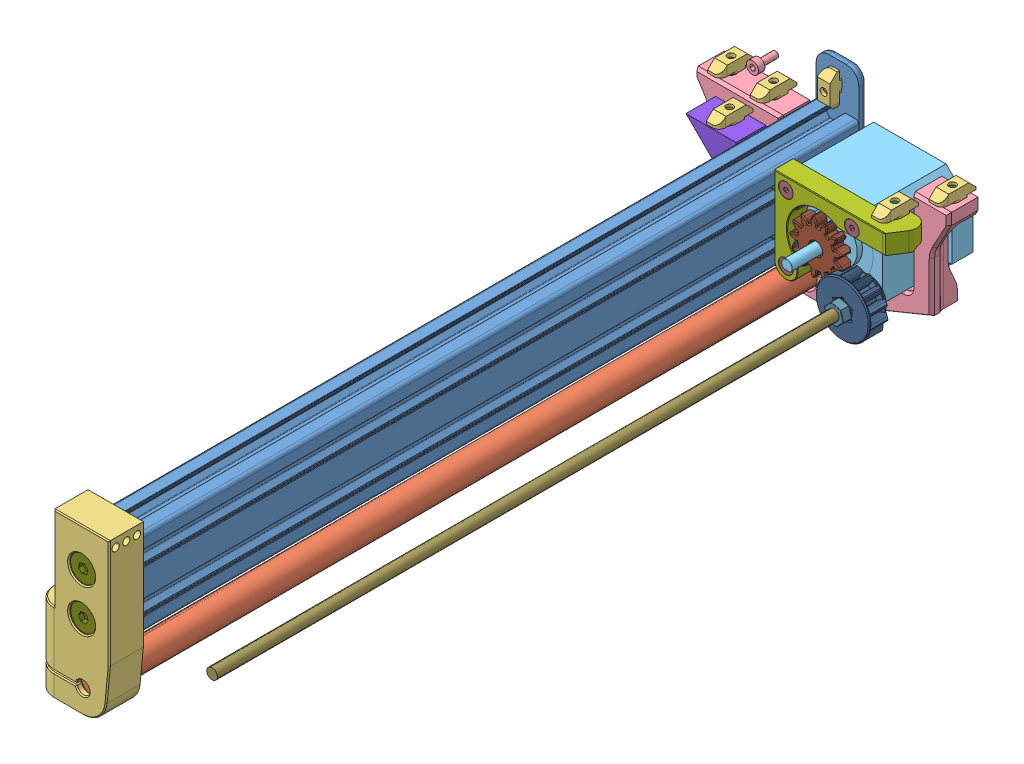
SolidWorks assembly 750Z, configuration Default. Lengths in mm.
Overall size (119 89 360).
38 component instances, 22 part files, 71 mates.
Components (placement in the parent):
- 458-1: 458 [Default] at origin size (20 40 350)
- 402-1: 402 [Default] at (0.5 -28 0) x (0.208946 -0.977927 0) z (0 0 1) size (12 12 350)
- 438-1: 438 [Default] at (0.5 -28 355) x (0 -1 0) z (0 0 -1) size (77 35 16)
- 437-1: 437 [Default] at (0.5 -28 3) x (0 1 0) z (0 0 1) size (67.1 119 22)
- 408-1: 408 [Default] at (31 9 -3) x (-1 0 0) z (0 0 1) size (50.7 42 57.75)
- 279-1: 279 [Default] at (45.4393 -5.4393 33.75) x (0.707107 -0.707107 0) z (0 0 1) size (10 10 4)
- 469-1: 469 [Default] at (31 9 30.75) x (0 1 0) z (0 0 1) size (42 57.25 15.29)
- 527-1: 527 [Default] at (-10 6 23.6304) x (-0.707107 0.707107 0) z (0.707107 0.707107 0) size (33.46 14 17)
- 1122-1: 1122 [Default] at (-12.95 20 30.6304) x (0 -0.98255 0.185999) z (-1 0 0) size (7.8 7.8 10)
- 441-1: 441 [Default] at (46.5 -6.5 34.25) x (-0.535081 -0.8448 0) z (0 0 1) size (25.3 25.3 13)
- 440-1: 440 [Default] at (31 9 36.2183) x (-1 0 0) z (0 0 1) size (24.94 25.13 8)
- 390-1: 390 [Default] at (46.5 -6.5 40.25) x (-0.169894 -0.985462 0) z (0 0 1) size (5 5 300)
- 466-1: 466 [Default] at (15.5 -6.5 38.025) x (0 1 0) z (0 0 1) size (6.75 6.75 12)
- 466-2: 466 [Default] at (46.5 24.5 38.025) x (0 1 0) z (0 0 1) size (6.75 6.75 12)
- 466-3: 466 [Default] at (15.5 24.5 38.025) x (0 1 0) z (0 0 1) size (6.75 6.75 12)
- 712-1: 712 [Default] at (46.5 -6.5 48.25) x (0.692186 0.721719 0) z (0 0 -1) size (9.24 8 4)
- 712-2: 712 [Default] at (46.5 -6.5 44.25) x (0.040994 0.999159 0) z (0 0 -1) size (9.24 8 4)
- 116-2: 116 [Default] at (14.95 0 35.25) x (0 -0.839931 -0.542693) z (1 0 0) size (7.8 7.8 12)
- 116-3: 116 [Default] at (14.95 20 35.25) x (0 -0.839931 -0.542693) z (1 0 0) size (7.8 7.8 12)
- 414-1: 414 [Default] at (0 20 351.25) x (-0.677245 -0.735758 0) z (0 0 1) size (12 12 16)
- 414-2: 414 [Default] at (0 0 351.15) x (0 1 0) z (0 0 1) size (12 12 16)
- 520-1: 520 [Default] at (-17.1 -36 345.2097) x (0.375961 0 0.926635) z (0 -1 0) size (5.7 5.7 38)
- 258-1: 258 [Default] at (-17.1 -1.6 345.2097) x (-0.866025 0 -0.5) z (0 -1 0) size (6.35 5.5 2.4)
- 503-1: 503 [Default] at (0 20 0) x (0 1 0) z (0 0 -1) size (40 20 3.7)
- 414-3: 414 [Default] at (0 20 0.1) x (0 1 0) z (0 0 -1) size (12 12 16)
- 115-1: 115 [Default] at (0 40 -0.75) x (0 1 0) z (0 0 -1) size (7.8 7.8 8)
- 497-1: 497 [Default] at (60 36 30) x (0 0 1) z (0 -1 0) size (16 6 5.5)
- 497-2: 497 [Default] at (-23 36 30.6304) x (0 0 -1) z (0 -1 0) size (16 6 5.5)
- 116-4: 116 [Default] at (57 25.05 30) x (-0.542693 0 0.839931) z (0 -1 0) size (7.8 7.8 12)
- 1122-5: 1122 [Default] at (-20 27.05 30.6304) x (0.98255 0 0.185999) z (0 -1 0) size (7.8 7.8 10)
- 116-6: 116 [Default] at (64 25.05 10) x (0.216044 0 -0.976384) z (0 -1 0) size (7.8 7.8 12)
- 116-7: 116 [Default] at (-20 25.05 10) x (0.999796 0 -0.020173) z (0 -1 0) size (7.8 7.8 12)
- 116-8: 116 [Default] at (-40 25.05 10) x (0.999796 0 -0.020173) z (0 -1 0) size (7.8 7.8 12)
- 497-3: 497 [Default] at (67 36 10) x (0 0 1) z (0 -1 0) size (16 6 5.5)
- 497-4: 497 [Default] at (-17 36.3767 10) x (0 0 1) z (0 -1 0) size (16 6 5.5)
- 497-5: 497 [Default] at (-37 36.4782 10) x (0 0 1) z (0 -1 0) size (16 6 5.5)
- 497-6: 497 [Default] at (3 40 6.4838) x (0 -1 0) z (0 0 -1) size (16 6 5.5)
- 111-1: 111 [Default] at (-25.6224 40.9837 11.2959) size (5.7 5.7 11)
Mates (geometry in assembly coordinates):
- Coincident7: coincident anti-aligned: plane of 458-1 through (9.8 -3.75 350) normal (0 0 1); plane of 438-1 through (0.5 -28 350) normal (0 0 -1)
- Coincident8: coincident anti-aligned: plane of 458-1 through (-10 23.7 350) normal (-1 0 0); plane of 438-1 through (-10 30 399.7214) normal (1 0 0)
- Coincident47: coincident anti-aligned: plane of 458-1 through (10 16.3 350) normal (1 0 0); plane of 438-1 through (10 30 399.7214) normal (-1 0 0)
- Coincident48: coincident anti-aligned: plane of 458-1 through (3.7 30 350) normal (0 1 0); plane of 438-1 through (-10 30 399.7214) normal (0 -1 0)
- Coincident56: coincident anti-aligned: plane of 458-1 through (10 16.3 350) normal (1 0 0); plane of 408-1 through (10 -8.007 30.75) normal (-1 0 0)
- Coincident117: coincident anti-aligned: plane of 458-1 through (10 16.3 350) normal (1 0 0); plane of 469-1 through (10 -6.5 39.75) normal (-1 0 0)
- Coincident130: coincident anti-aligned: plane of 458-1 through (-10 3.65 350) normal (-1 0 0); plane of 527-1 through (-10 30 37.6304) normal (1 0 0)
- Concentric7: concentric aligned: cylinder of 402-1 through (0.5 -28 350) axis (0 0 -1) radius 6; cylinder of 438-1 through (0.5 -28 371.9706) axis (0 0 -1) radius 6
- Concentric21: concentric aligned: cylinder of 402-1 through (0.5 -28 350) axis (0 0 -1) radius 6; cylinder of 437-1 through (0.5 -28 17) axis (0 0 -1) radius 6.1
- Coincident170: coincident anti-aligned: plane of 402-1 through (0.5 -28 0) normal (0 0 -1); circle of 437-1
- Distance6: distance = 0.5 mm anti-aligned: plane of 279-1 through (47.5607 -7.5607 31.25) normal (0 0 -1); plane of 408-1 through (31 9 30.75) normal (0 0 1)
- Concentric20: concentric anti-aligned: cylinder of 408-1 through (46.5 -6.5 25.75) axis (0 0 1) radius 1.5; cylinder of 279-1 through (46.5 -6.5 36.25) axis (0 0 -1) radius 1.5
- Coincident118: coincident anti-aligned: plane of 408-1 through (31 9 30.75) normal (0 0 1); plane of 469-1 through (31 9 30.75) normal (0 0 -1)
- Concentric75: concentric anti-aligned: cylinder of 440-1 through (31 9 26.4376) axis (0 0 1) radius 2.525; cylinder of 408-1 through (31 9 54.75) axis (0 0 -1) radius 2.5
- Parallel13: parallel anti-aligned: plane of 408-1 through (32.5 7 54.75) normal (0 -1 0); plane of 440-1 through (32.5413 7 26.4376) normal (0 1 0)
- Coincident138: coincident anti-aligned: plane of 279-1 through (48.091 -8.091 35.25) normal (0 0 1); plane of 441-1 through (46.5 -6.5 35.25) normal (0 0 -1)
- Concentric74: concentric anti-aligned: cylinder of 279-1 through (46.5 -6.5 36.25) axis (0 0 -1) radius 1.5; cylinder of 441-1 through (46.5 -6.5 31.25) axis (0 0 1) radius 3.3
- Coincident234: coincident: cone of 469-1 through (15.5 -6.5 37.95) axis (0 0 -1); circle of 466-1
- Coincident239: coincident: cone of 469-1 through (15.5 24.5 37.95) axis (0 0 -1); circle of 466-3
- Coincident240: coincident: cone of 469-1 through (46.5 24.5 37.95) axis (0 0 -1); circle of 466-2
- Concentric196: concentric anti-aligned: cylinder of 469-1 through (24 20 35.25) axis (-1 0 0) radius 2.15; cylinder of 116-3 through (5.25 20 35.25) axis (1 0 0) radius 2
- Coincident259: coincident: cone of 469-1 through (15.5 20 35.25) axis (-1 0 0); circle of 116-3
- Concentric197: concentric anti-aligned: cylinder of 469-1 through (24 0 35.25) axis (-1 0 0) radius 2.15; cylinder of 116-2 through (5.25 0 35.25) axis (1 0 0) radius 2
- Coincident260: coincident: cone of 469-1 through (15.5 0 35.25) axis (-1 0 0); circle of 116-2
- Concentric72: concentric anti-aligned: cylinder of 527-1 through (-34 20 30.6304) axis (1 0 0) radius 2.15; cylinder of 1122-1 through (-5.25 20 30.6304) axis (-1 0 0) radius 2
- Coincident137: coincident: cone of 527-1 through (-13.5 20 30.6304) axis (1 0 0); circle of 1122-1
- Coincident175: coincident anti-aligned: plane of 441-1 through (29.6234 -15.3419 40.25) normal (0 0 1); plane of 390-1 through (46.5 -6.5 40.25) normal (0 0 -1)
- Coincident252: coincident anti-aligned: plane of 441-1 through (29.6234 -15.3419 40.25) normal (0 0 1); plane of 712-2 through (46.5 -6.5 40.25) normal (0 0 -1)
- Concentric187: concentric anti-aligned: cylinder of 390-1 through (46.5 -6.5 340.25) axis (0 0 -1) radius 2.5; cylinder of 712-1 through (46.5 -6.5 44.25) axis (0 0 1) radius 2.1
- Concentric189: concentric anti-aligned: cylinder of 390-1 through (46.5 -6.5 340.25) axis (0 0 -1) radius 2.5; cylinder of 712-2 through (46.5 -6.5 40.25) axis (0 0 1) radius 2.1
- Coincident253: coincident anti-aligned: plane of 712-1 through (46.5 -6.5 44.25) normal (0 0 -1); plane of 712-2 through (46.5 -6.5 44.25) normal (0 0 1)
- Concentric267: concentric aligned: cylinder of 438-1 through (0 20 339) axis (0 0 1) radius 3.05; cylinder of 414-1 through (0 20 338.25) axis (0 0 1) radius 3
- Coincident326: coincident: cone of 438-1 through (0 20 354.3) axis (0 0 -1); circle of 414-1
- Coincident327: coincident: cone of 438-1 through (0 0 351.3) axis (0 0 -1); circle of 414-2
- Concentric268: concentric aligned: cylinder of 438-1 through (-17.1 33 345.2097) axis (0 -1 0) radius 1.65; cylinder of 520-1 through (-17.1 -1 345.2097) axis (0 -1 0) radius 1.5
- Coincident328: coincident anti-aligned: plane of 438-1 through (-17.1 -36 345.2097) normal (0 -1 0); plane of 520-1 through (-17.1 -36 345.2097) normal (0 1 0)
- Parallel42: parallel anti-aligned: plane of 438-1 through (-14.3 33 339) normal (-1 0 0); plane of 258-1 through (-14.35 -4 343.622) normal (1 0 0)
- Coincident329: coincident anti-aligned: plane of 438-1 through (0.5 -4 355) normal (0 1 0); plane of 258-1 through (-17.1 -4 345.2097) normal (0 -1 0)
- Concentric275: concentric anti-aligned: cylinder of 520-1 through (-17.1 -1 345.2097) axis (0 -1 0) radius 1.5; cylinder of 258-1 through (-17.1 -4 345.2097) axis (0 1 0) radius 1.25
- Coincident330: coincident anti-aligned: plane of 458-1 through (9.8 -3.75 0) normal (0 0 -1); plane of 503-1 through (0 20 0) normal (0 0 1)
- Concentric276: concentric aligned: cylinder of 458-1 through (0 20 350) axis (0 0 -1) radius 2.75; cylinder of 503-1 through (0 20 -3) axis (0 0 -1) radius 6.1
- Parallel43: parallel aligned: plane of 458-1 through (3.7 30 350) normal (0 1 0); plane of 503-1 through (10 50 -3.7) normal (0 1 0)
- Concentric282: concentric aligned: cylinder of 458-1 through (0 20 350) axis (0 0 -1) radius 2.75; cylinder of 414-3 through (0 20 13.1) axis (0 0 -1) radius 3
- Coincident339: coincident: cone of 503-1 through (0 20 0) axis (0 0 1); circle of 414-3
- Concentric281: concentric anti-aligned: cylinder of 503-1 through (0 40 -3.7) axis (0 0 1) radius 2.15; cylinder of 115-1 through (0 40 4.95) axis (0 0 -1) radius 2
- Coincident338: coincident: cone of 503-1 through (0 40 -1.3) axis (0 0 1); circle of 115-1
- Concentric271: concentric anti-aligned: cylinder of 116-4 through (57 34.75 30) axis (0 -1 0) radius 2; cylinder of 469-1 through (57 -12 30) axis (0 1 0) radius 2.15
- Coincident335: coincident: circle of 116-4; cone of 469-1 through (57 22.5 30) axis (0 1 0)
- Concentric63: concentric aligned: cylinder of 497-1 through (57 36 30) axis (0 -1 0) radius 1.65; cylinder of 116-4 through (57 34.75 30) axis (0 -1 0) radius 2
- Concentric272: concentric anti-aligned: cylinder of 1122-5 through (-20 34.75 30.6304) axis (0 -1 0) radius 2; cylinder of 527-1 through (-20 6 30.6304) axis (0 1 0) radius 2.15
- Coincident337: coincident: circle of 1122-5; cone of 527-1 through (-20 24.4 30.6304) axis (0 1 0)
- Concentric71: concentric aligned: cylinder of 1122-5 through (-20 34.75 30.6304) axis (0 -1 0) radius 2; cylinder of 497-2 through (-20 36 30.6304) axis (0 -1 0) radius 1.65
- Coincident340: coincident: cone of 437-1 through (64 24.5 10) axis (0 1 0); circle of 116-6
- Coincident331: coincident: cone of 437-1 through (-20 24.5 10) axis (0 1 0); circle of 116-7
- Coincident332: coincident: cone of 437-1 through (-40 24.5 10) axis (0 1 0); circle of 116-8
- Concentric283: concentric aligned: cylinder of 116-6 through (64 34.75 10) axis (0 -1 0) radius 2; cylinder of 497-3 through (64 36 10) axis (0 -1 0) radius 1.65
- Parallel44: parallel aligned: plane of 497-1 through (54 36 30) normal (-1 0 0); plane of 497-3 through (61 36 10) normal (-1 0 0)
- Concentric285: concentric aligned: cylinder of 116-7 through (-20 34.75 10) axis (0 -1 0) radius 2; cylinder of 497-4 through (-20 36.3767 10) axis (0 -1 0) radius 1.65
- Concentric286: concentric aligned: cylinder of 116-8 through (-40 34.75 10) axis (0 -1 0) radius 2; cylinder of 497-5 through (-40 36.4782 10) axis (0 -1 0) radius 1.65
- Parallel45: parallel aligned: plane of 497-4 through (-23 36.3767 10) normal (-1 0 0); plane of 497-5 through (-43 36.4782 10) normal (-1 0 0)
- Parallel46: parallel aligned: plane of 497-1 through (54 36 30) normal (-1 0 0); plane of 497-4 through (-23 36.3767 10) normal (-1 0 0)
- Parallel47: parallel aligned: plane of 458-1 through (-10 3.65 350) normal (-1 0 0); plane of 497-4 through (-23 36.3767 10) normal (-1 0 0)
- Concentric287: concentric aligned: cylinder of 115-1 through (0 40 4.95) axis (0 0 -1) radius 2; cylinder of 497-6 through (0 40 6.4838) axis (0 0 -1) radius 1.65
- Parallel48: parallel aligned: plane of 497-5 through (-43 36.4782 10) normal (-1 0 0); plane of 497-6 through (-3 40 6.4838) normal (-1 0 0)
- Distance7: distance = 20 mm aligned: plane of 497-1 through (54 31.5 33.85) normal (0 0 1); plane of 497-3 through (61 31.5 13.85) normal (0 0 1)
- Distance10: distance = 10 mm aligned: plane of 503-1 through (0 20 0) normal (0 0 1); plane of assembly through (0 0 10) normal (0 0 1)
- Concentric288: concentric aligned: cylinder of 116-6 through (64 34.75 10) axis (0 -1 0) radius 2; cylinder of 497-3 through (64 36 10) axis (0 -1 0) radius 1.65
- Coincident341: coincident aligned: plane of 469-1 through (10 30 39.75) normal (0 1 0); plane of 527-1 through (-34 30 37.6304) normal (0 1 0)
- Coincident342: coincident aligned: plane of 458-1 through (3.7 30 350) normal (0 1 0); plane of 469-1 through (10 30 39.75) normal (0 1 0)
- Coincident343: coincident aligned: plane of 497-1 through (54 30.5 26.15) normal (0 -1 0); plane of 497-3 through (61 30.5 6.15) normal (0 -1 0)
- Distance11: distance = 1.5 mm anti-aligned: plane of 497-3 through (61 31.5 18) normal (0 -1 0); plane of 437-1 through (69 30 17) normal (0 1 0)
